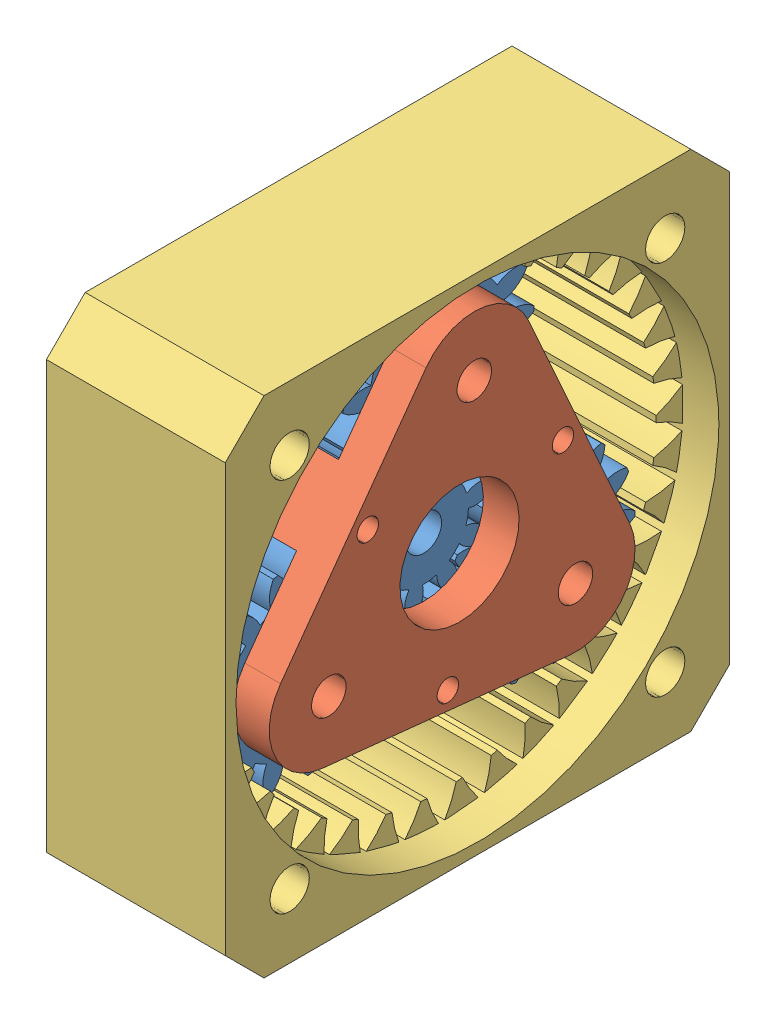
SolidWorks assembly test, configuration Default. Lengths in mm.
Overall size (15 45.06 44.52).
8 component instances, 5 part files, 21 mates.
Components (placement in the parent):
- spur gear_am-1: spur gear_am [Metric - Spur gear 1M 10T 20PA 10FW ---S10N75H50L3N] at (-21.3284 1.4769 5.7011) x (1 0 0) z (0 0.476159 0.879359) size (10 11.48 12)
- spur gear_am-2: spur gear_am [Metric - Spur gear 1M 14T 20PA 10FW ---S14N75H50L3N] at (-21.3284 -5.5681 -4.0242) x (1 0 0) z (0 0.384553 -0.923103) size (10 15.69 16)
- spur gear_am-3: spur gear_am [Metric - Spur gear 1M 14T 20PA 10FW ---S14N75H50L3N] at (-21.3284 -3.4229 16.6649) x (1 0 0) z (0 -0.470824 -0.882227) size (10 15.69 16)
- spur gear_am-4: spur gear_am [Metric - Spur gear 1M 14T 20PA 10FW ---S14N75H50L3N] at (-21.3284 13.4218 4.4627) x (1 0 0) z (0 -0.465575 -0.885008) size (10 15.69 16)
- holder-2: holder [Default] at (-8.3284 1.4769 5.7011) x (0 0.809842 -0.586648) z (-1 0 0) size (30.8 28.01 13.5)
- carrier4-1: carrier4 [Default] at (13.3536 -4.3795 -8.8852) size (15 42.3 42.3)
- cap-1: cap [Default] at (-21.8284 1.7604 -3.1037) x (0 0 1) z (-1 0 0) size (42.26 42.26 7.5) (hidden)
- pully-1: pully [Default] at (-21.8284 1.4769 5.7011) x (0 0.103131 0.994668) z (-1 0 0) size (30.8 28.01 28.5) (hidden)
Mates (geometry in assembly coordinates):
- Concentric4: concentric: cylinder of spur gear_am-4 through (28.6716 13.4218 4.4627) axis (-1 0 0) radius 1.5; cylinder of holder-2 through (-11.3284 13.4218 4.4627) axis (1 0 0) radius 1.45
- Concentric5: concentric: cylinder of spur gear_am-3 through (28.6716 -3.4229 16.6649) axis (-1 0 0) radius 1.5; cylinder of holder-2 through (-11.3284 -3.4229 16.6649) axis (1 0 0) radius 1.45
- Concentric6: concentric: cylinder of spur gear_am-2 through (28.6716 -5.5681 -4.0242) axis (-1 0 0) radius 1.5; cylinder of holder-2 through (-11.3284 -5.5681 -4.0242) axis (1 0 0) radius 1.45
- Coincident12: coincident: plane of spur gear_am-2 through (-11.3284 -5.5681 -4.0242) normal (1 0 0); plane of spur gear_am-4 through (-11.3284 13.4218 4.4627) normal (1 0 0)
- Coincident13: coincident: plane of spur gear_am-3 through (-11.3284 -3.4229 16.6649) normal (1 0 0); plane of spur gear_am-4 through (-11.3284 13.4218 4.4627) normal (1 0 0)
- Coincident14: coincident: plane of spur gear_am-1 through (-11.3284 1.4769 5.7011) normal (1 0 0); plane of spur gear_am-4 through (-11.3284 13.4218 4.4627) normal (1 0 0)
- Coincident15: coincident: plane of spur gear_am-1 through (-11.3284 1.4769 5.7011) normal (1 0 0); plane of holder-2 through (-11.3284 -3.4229 16.6649) normal (-1 0 0)
- Concentric9: concentric: cylinder of holder-2 through (-11.3284 1.4769 5.7011) axis (1 0 0) radius 5; cylinder of carrier4-1 through (-9.8284 1.4769 5.7011) axis (-1 0 0) radius 20.251
- GearMate1: gear = 140 : 100 mm: circle of spur gear_am-1; circle of spur gear_am-4
- GearMate2: gear = 140 : 100 mm: circle of spur gear_am-1; circle of spur gear_am-3
- GearMate3: gear = 100 : 140 mm: circle of spur gear_am-2; circle of spur gear_am-1
- Concentric10: concentric: circle of spur gear_am-1; circle of holder-2
- GearMate5: gear = 380 : 140 mm: circle of spur gear_am-3; circle of carrier4-1
- Coincident19: coincident: plane of carrier4-1 through (-21.8284 1.4769 -12.2989) normal (-1 0 0); plane of cap-1 through (-21.8284 1.7604 -3.1037) normal (1 0 0)
- Concentric13: concentric: cylinder of carrier4-1 through (-6.8284 17.2269 -10.0489) axis (-1 0 0) radius 1.65; cylinder of cap-1 through (-26.3284 17.2269 -10.0489) axis (1 0 0) radius 1.75
- Concentric14: concentric: cylinder of carrier4-1 through (-6.8284 -14.2731 21.4511) axis (-1 0 0) radius 1.65; cylinder of cap-1 through (-26.3284 -14.2731 21.4511) axis (1 0 0) radius 1.75
- Coincident20: coincident: plane of carrier4-1 through (-21.8284 1.4769 -12.2989) normal (-1 0 0); plane of pully-1 through (-21.8284 -5.5681 -4.0242) normal (1 0 0)
- Concentric15: concentric: circle of holder-2; cylinder of pully-1 through (-21.8284 1.4769 5.7011) axis (-1 0 0) radius 2.8
- Concentric16: concentric: cylinder of spur gear_am-2 through (28.6716 -5.5681 -4.0242) axis (-1 0 0) radius 1.5; cylinder of pully-1 through (-25.3284 -5.5681 -4.0242) axis (1 0 0) radius 1.5
- Concentric17: concentric: cylinder of spur gear_am-4 through (28.6716 13.4218 4.4627) axis (-1 0 0) radius 1.5; cylinder of pully-1 through (-25.3284 13.4218 4.4627) axis (1 0 0) radius 1.5
- Concentric18: concentric: cylinder of spur gear_am-3 through (28.6716 -3.4229 16.6649) axis (-1 0 0) radius 1.5; cylinder of pully-1 through (-25.3284 -3.4229 16.6649) axis (1 0 0) radius 1.5
